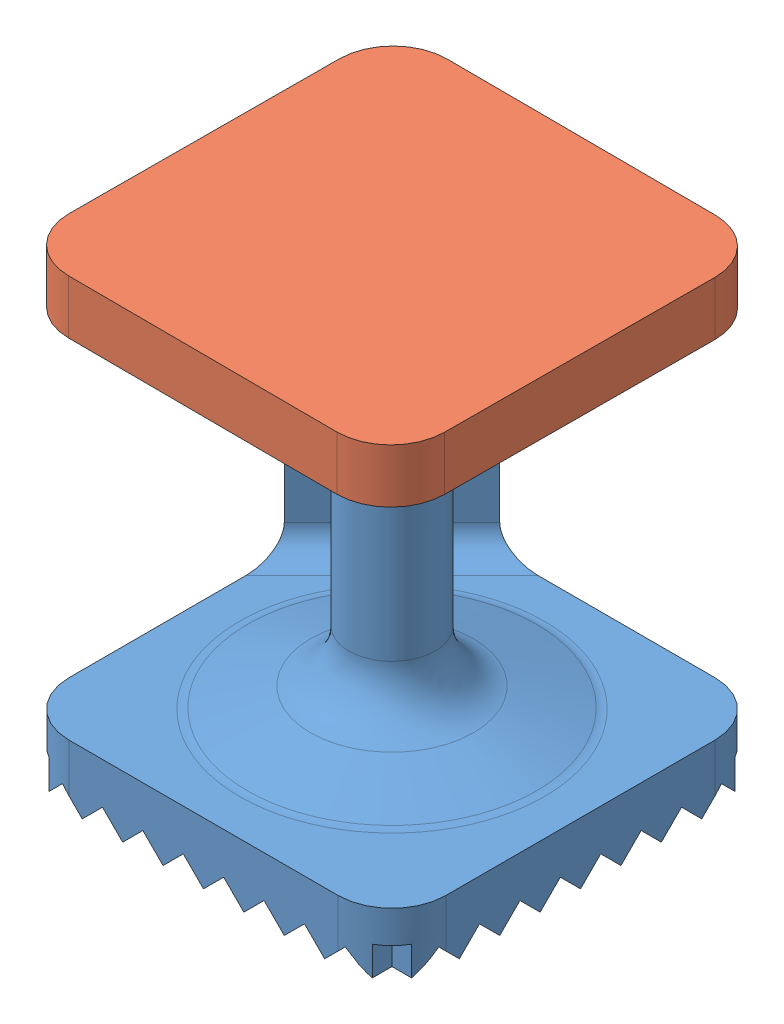
SolidWorks assembly 装配, configuration 默认. Lengths in mm.
Overall size (70.29 85.94 70.29).
2 component instances, 2 part files, 2 mates.
Components (placement in the parent):
- 主体-1: 主体 [默认] at origin size (70 81.44 70)
- 盖子-1: 盖子 [默认] at (0 80.5 0) x (-0.004084 0 0.999992) z (0.999992 0 0.004084) size (70 10 70)
Mates (geometry in assembly coordinates):
- 同心2: concentric: cylinder of assembly; cylinder of assembly; cylinder of 主体-1 through (0 76 0) axis (0 -1 0) radius 4.5; cylinder of 盖子-1 through (0 70.5 0) axis (0 1 0) radius 4
- 重合5: coincident: plane of assembly; plane of assembly; plane of 主体-1 through (0 76 0) normal (0 1 0); plane of 盖子-1 through (0 76 0) normal (0 -1 0)
